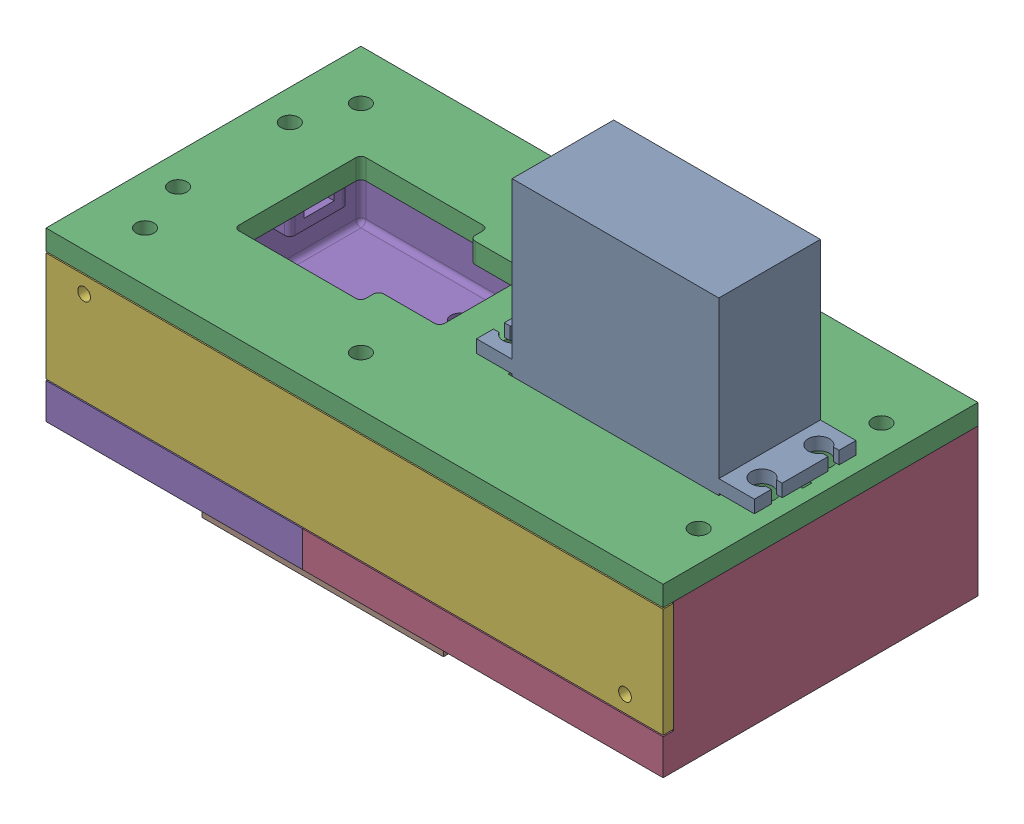
SolidWorks assembly Gearbox, configuration Default. Lengths in mm.
Overall size (121.5 71.3 62).
7 component instances, 6 part files, 18 mates.
Components (placement in the parent):
- Big Servo-1: Big Servo [Default] at (40.62 46.55 0) x (-1 0 0) z (0 1 0) size (54.7 20 45.2)
- 180gear-1: 180gear [Default] at (30 23.1 0) x (0 -1 0) z (-0.87579 0 0.482693) size (10 41.91 41.91)
- 360housing_top-1: 360housing_top [Default] at (0 29 0) size (121.5 4 62)
- 360housing_bottom-1: 360housing_bottom [Default] at origin size (121.5 29 62)
- 360housing_cover-1: 360housing_cover [Default] at (10.25 18 29) size (121.5 21.5 2)
- 360housing_support-1: 360housing_support [Default] at (0 -5 -20) size (47.5 5 6)
- 360housing_support-2: 360housing_support [Default] at (0 -5 24) size (47.5 5 6)
Mates (geometry in assembly coordinates):
- Concentric2: concentric anti-aligned: cylinder of Big Servo-1 through (30 21.1 0) axis (0 1 0) radius 3; cylinder of 180gear-1 through (30 11.1 0) axis (0 -1 0) radius 1.7
- Coincident3: coincident anti-aligned: plane of Big Servo-1 through (30 21.1 0) normal (0 -1 0); plane of 180gear-1 through (30 21.1 0) normal (0 1 0)
- Coincident4: coordinate: point of 360housing_bottom-1
- Coincident5: coincident anti-aligned: plane of 360housing_top-1 through (0 29 0) normal (0 -1 0); plane of 360housing_bottom-1 through (0 29 0) normal (0 1 0)
- Concentric3: concentric aligned: cylinder of 360housing_top-1 through (-44.5 29 -11) axis (0 1 0) radius 1.75; cylinder of 360housing_bottom-1 through (-44.5 14.0503 -11) axis (0 1 0) radius 1.75
- Concentric4: concentric aligned: cylinder of 360housing_top-1 through (-44.5 29 11) axis (0 1 0) radius 1.75; cylinder of 360housing_bottom-1 through (-44.5 14.0503 11) axis (0 1 0) radius 1.75
- Coincident6: coincident anti-aligned: plane of 360housing_bottom-1 through (0 0 0) normal (0 -1 0); plane of 360housing_support-1 through (0 0 -20) normal (0 1 0)
- Concentric5: concentric anti-aligned: cylinder of 360housing_bottom-1 through (20 0 -20) axis (0 1 0) radius 1.75; cylinder of 360housing_support-1 through (20 0 -20) axis (0 -1 0) radius 1.75
- Concentric6: concentric anti-aligned: cylinder of 360housing_bottom-1 through (-20 0 -20) axis (0 1 0) radius 1.75; cylinder of 360housing_support-1 through (-20 0 -20) axis (0 -1 0) radius 1.75
- Coincident7: coincident anti-aligned: plane of 360housing_bottom-1 through (0 0 0) normal (0 -1 0); plane of 360housing_support-2 through (0 0 24) normal (0 1 0)
- Concentric7: concentric anti-aligned: cylinder of 360housing_bottom-1 through (20 0 24) axis (0 1 0) radius 1.75; cylinder of 360housing_support-2 through (20 0 24) axis (0 -1 0) radius 1.75
- Concentric8: concentric anti-aligned: cylinder of 360housing_bottom-1 through (-20 0 24) axis (0 1 0) radius 1.75; cylinder of 360housing_support-2 through (-20 0 24) axis (0 -1 0) radius 1.75
- Coincident8: coincident anti-aligned: plane of 360housing_bottom-1 through (0 29 29) normal (0 0 1); plane of 360housing_cover-1 through (10.25 18 29) normal (0 0 -1)
- Concentric9: concentric aligned: cylinder of 360housing_bottom-1 through (-43 25.5 23.5) axis (0 0 1) radius 1.25; cylinder of 360housing_cover-1 through (-43 25.5 29) axis (0 0 1) radius 1.25
- Concentric10: concentric aligned: cylinder of 360housing_bottom-1 through (63.5 10.5 23.5) axis (0 0 1) radius 1.25; cylinder of 360housing_cover-1 through (63.5 10.5 29) axis (0 0 1) radius 1.25
- Coincident9: coincident anti-aligned: plane of Big Servo-1 through (13.27 33 10) normal (0 -1 0); plane of 360housing_top-1 through (0 33 0) normal (0 1 0)
- Concentric11: concentric anti-aligned: cylinder of Big Servo-1 through (16.18 66.3 -5.6) axis (0 -1 0) radius 2.1; cylinder of 360housing_top-1 through (16.18 29 -5.6) axis (0 1 0) radius 2.5
- Concentric12: concentric anti-aligned: cylinder of Big Servo-1 through (16.18 66.3 5.6) axis (0 -1 0) radius 2.1; cylinder of 360housing_top-1 through (16.18 29 5.6) axis (0 1 0) radius 2.5
